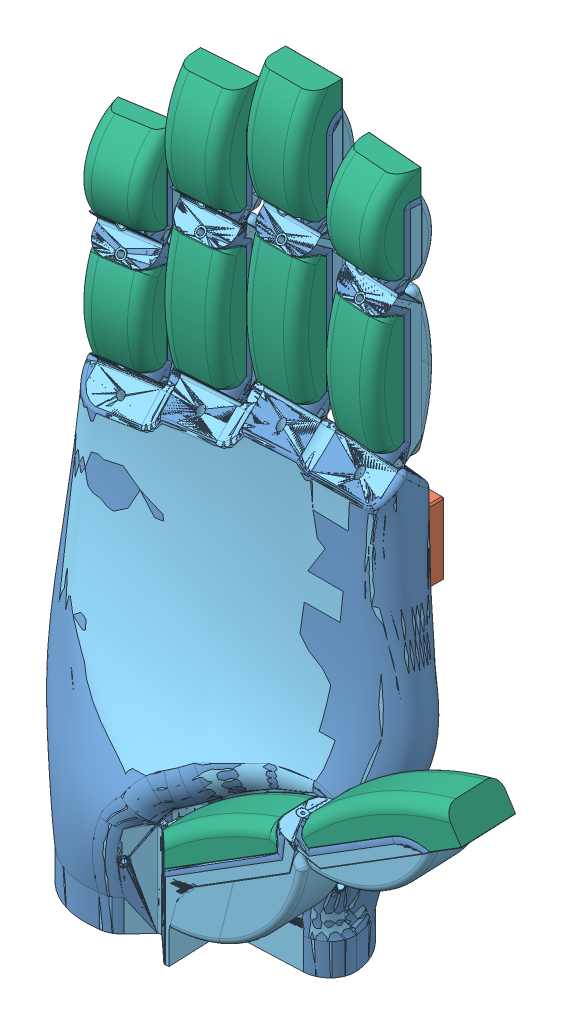
SolidWorks assembly HandAssembly2, configuration Default. Lengths in mm.
Overall size (153.66 227.4 65.45).
29 component instances, 6 part files, 43 mates.
Components (placement in the parent):
- Hand-1: Hand [Default] at origin size (147.58 222.67 61.94)
- ServoAssem-1: ServoAssem [Default] at (17.11 -26.63 -24.3814) x (1 0 0) z (0 -1 0) size (13.8 32.4 32)
  - AGFRC Micro Servo-1: AGFRC Micro Servo [Default] at origin size (12 31.6 32)
  - Pulley-1: Pulley [Default] at (0 28.4 5.5) x (1 0 0) z (0 -1 0) size (13.8 13.8 4)
- ServoAssem-2: ServoAssem [Default] at (-4 -26.63 -24.3814) x (1 0 0) z (0 -1 0) size (13.8 32.4 32)
  - AGFRC Micro Servo-1: AGFRC Micro Servo [Default] at origin size (12 31.6 32)
  - Pulley-1: Pulley [Default] at (0 28.4 5.5) x (1 0 0) z (0 -1 0) size (13.8 13.8 4)
- ServoAssem-3: ServoAssem [Default] at (-20.229 -26.63 -24.3814) x (1 0 0) z (0 -1 0) size (13.8 32.4 32)
  - AGFRC Micro Servo-1: AGFRC Micro Servo [Default] at origin size (12 31.6 32)
  - Pulley-1: Pulley [Default] at (0 28.4 5.5) x (1 0 0) z (0 -1 0) size (13.8 13.8 4)
- ServoAssem-4: ServoAssem [Default] at (-38.46 -26.63 -24.3814) x (1 0 0) z (0 -1 0) size (13.8 32.4 32)
  - AGFRC Micro Servo-1: AGFRC Micro Servo [Default] at origin size (12 31.6 32)
  - Pulley-1: Pulley [Default] at (0 28.4 5.5) x (1 0 0) z (0 -1 0) size (13.8 13.8 4)
- ServoAssem-6: ServoAssem [Default] at (1.5 -77.13 -24.3814) x (0 -1 0) z (-1 0 0) size (13.8 32.4 32)
  - AGFRC Micro Servo-1: AGFRC Micro Servo [Default] at origin size (12 31.6 32)
  - Pulley-1: Pulley [Default] at (0 28.4 5.5) x (1 0 0) z (0 -1 0) size (13.8 13.8 4)
- ServoAssem-7: ServoAssem [Default] at (1.4 -114.356 -2.7814) x (0 0 -1) z (0 1 0) size (13.8 32.4 32)
  - AGFRC Micro Servo-1: AGFRC Micro Servo [Default] at origin size (12 31.6 32)
  - Pulley-1: Pulley [Default] at (0 28.4 5.5) x (1 0 0) z (0 -1 0) size (13.8 13.8 4)
- SensorPCB-1: SensorPCB [Default] at (25.2355 63.12 -1.7931) x (0.996917 0 0.078459) z (0 -1 0) size (12.4 3.2 10.5)
- SensorPCB-2: SensorPCB [Default] at (25.2355 23.12 -1.7931) x (0.996917 0 0.078459) z (0 -1 0) size (12.4 3.2 10.5)
- SensorPCB-6: SensorPCB [Default] at (0 70.75 -1.6) x (1 0 0) z (0 -1 0) size (12.4 3.2 10.5)
- SensorPCB-8: SensorPCB [Default] at (0 25.5 -1.6) x (1 0 0) z (0 -1 0) size (12.4 3.2 10.5)
- SensorPCB-10: SensorPCB [Default] at (-24.3431 60.45 0.1261) x (0.997453 0 -0.071323) z (0 -1 0) size (12.4 3.2 10.5)
- SensorPCB-12: SensorPCB [Default] at (-24.7221 10.21 0.1532) x (-0.997453 0 0.071323) z (0 1 0) size (12.4 3.2 10.5)
- SensorPCB-14: SensorPCB [Default] at (-46.7194 41.62 3.7142) x (0.986771 0 -0.162121) z (0 -1 0) size (12.4 3.2 10.5)
- SensorPCB-16: SensorPCB [Default] at (-46.7194 7.27 3.7142) x (0.986771 0 -0.162121) z (0 -1 0) size (12.4 3.2 10.5)
- RidgedBackPlates-1: RidgedBackPlates [Default] at origin size (147.58 222.67 61.94)
- SquishyFrontPieces-1: SquishyFrontPieces [Default] at origin size (143.98 202.57 46.2)
Mates (geometry in assembly coordinates):
- Width1: width anti-aligned: plane of Hand-1 through (23.61 -50.13 46.9567) normal (-1 0 0); plane of ServoAssem-1/AGFRC Micro Servo-1 through (10.61 -50.13 46.9567) normal (1 0 0); plane of Hand-1 through (23.11 -26.63 -24.3814) normal (1 0 0); plane of ServoAssem-1/AGFRC Micro Servo-1 through (11.11 -26.63 -24.3814) normal (-1 0 0)
- Width2: width aligned: plane of Hand-1 through (23.61 -50.13 46.9567) normal (0 1 0); plane of ServoAssem-1/AGFRC Micro Servo-1 through (10.61 -26.13 46.9567) normal (0 -1 0); plane of Hand-1 through (23.11 -26.63 -24.3814) normal (0 1 0); plane of ServoAssem-1/AGFRC Micro Servo-1 through (23.11 -49.63 -24.3814) normal (0 -1 0)
- Coincident1: coincident anti-aligned: plane of Hand-1 through (0 0 -2.4814) normal (0 0 -1); plane of ServoAssem-1/AGFRC Micro Servo-1 through (23.11 -26.63 -2.4814) normal (0 0 1)
- Width3: width anti-aligned: plane of Hand-1 through (-10.5 -50.13 46.9567) normal (1 0 0); plane of ServoAssem-2/AGFRC Micro Servo-1 through (2.5 -50.13 46.9567) normal (-1 0 0); plane of Hand-1 through (2 -26.63 -24.3814) normal (1 0 0); plane of ServoAssem-2/AGFRC Micro Servo-1 through (-10 -26.63 -24.3814) normal (-1 0 0)
- Width4: width aligned: plane of Hand-1 through (2.5 -50.13 46.9567) normal (0 1 0); plane of ServoAssem-2/AGFRC Micro Servo-1 through (2.5 -26.13 46.9567) normal (0 -1 0); plane of Hand-1 through (2 -26.63 -24.3814) normal (0 1 0); plane of ServoAssem-2/AGFRC Micro Servo-1 through (2 -49.63 -24.3814) normal (0 -1 0)
- Coincident2: coincident anti-aligned: plane of Hand-1 through (0 0 -2.4814) normal (0 0 -1); plane of ServoAssem-2/AGFRC Micro Servo-1 through (2 -26.63 -2.4814) normal (0 0 1)
- Coincident3: coincident anti-aligned: plane of Hand-1 through (0 0 -2.4814) normal (0 0 -1); plane of ServoAssem-3/AGFRC Micro Servo-1 through (-14.229 -26.63 -2.4814) normal (0 0 1)
- Width5: width anti-aligned: plane of Hand-1 through (-26.729 -50.13 46.9567) normal (1 0 0); plane of ServoAssem-3/AGFRC Micro Servo-1 through (-13.729 -50.13 46.9567) normal (-1 0 0); plane of Hand-1 through (-14.229 -26.63 -24.3814) normal (1 0 0); plane of ServoAssem-3/AGFRC Micro Servo-1 through (-26.229 -26.63 -24.3814) normal (-1 0 0)
- Width6: width aligned: plane of Hand-1 through (-13.729 -50.13 46.9567) normal (0 1 0); plane of ServoAssem-3/AGFRC Micro Servo-1 through (-13.729 -26.13 46.9567) normal (0 -1 0); plane of Hand-1 through (-14.229 -26.63 -24.3814) normal (0 1 0); plane of ServoAssem-3/AGFRC Micro Servo-1 through (-14.229 -49.63 -24.3814) normal (0 -1 0)
- Coincident4: coincident anti-aligned: plane of Hand-1 through (0 0 -2.4814) normal (0 0 -1); plane of ServoAssem-4/AGFRC Micro Servo-1 through (-32.46 -26.63 -2.4814) normal (0 0 1)
- Width7: width anti-aligned: plane of Hand-1 through (-44.96 -50.13 46.9567) normal (1 0 0); plane of ServoAssem-4/AGFRC Micro Servo-1 through (-31.96 -26.13 46.9567) normal (-1 0 0); plane of Hand-1 through (-32.46 -26.63 -24.3814) normal (1 0 0); plane of ServoAssem-4/AGFRC Micro Servo-1 through (-44.46 -26.63 -24.3814) normal (-1 0 0)
- Width8: width aligned: plane of Hand-1 through (-31.96 -50.13 46.9567) normal (0 1 0); plane of ServoAssem-4/AGFRC Micro Servo-1 through (-31.96 -26.13 46.9567) normal (0 -1 0); plane of Hand-1 through (-32.46 -26.63 -24.3814) normal (0 1 0); plane of ServoAssem-4/AGFRC Micro Servo-1 through (-32.46 -49.63 -24.3814) normal (0 -1 0)
- Width13: width anti-aligned: plane of Hand-1 through (2 -83.63 46.9567) normal (0 1 0); plane of ServoAssem-6/AGFRC Micro Servo-1 through (-22 -70.63 46.9567) normal (0 -1 0); plane of Hand-1 through (1.5 -83.13 -24.3814) normal (0 -1 0); plane of ServoAssem-6/AGFRC Micro Servo-1 through (1.5 -71.13 -24.3814) normal (0 1 0)
- Width14: width aligned: plane of Hand-1 through (-22 -83.63 46.9567) normal (1 0 0); plane of ServoAssem-6/AGFRC Micro Servo-1 through (2 -83.63 46.9567) normal (-1 0 0); plane of Hand-1 through (1.5 -83.13 -24.3814) normal (1 0 0); plane of ServoAssem-6/AGFRC Micro Servo-1 through (-21.5 -83.13 -24.3814) normal (-1 0 0)
- Coincident6: coincident anti-aligned: plane of Hand-1 through (0 0 -2.4814) normal (0 0 -1); plane of ServoAssem-6/AGFRC Micro Servo-1 through (1.5 -83.13 -2.4814) normal (0 0 1)
- Width16: width aligned: plane of Hand-1 through (1.9 -90.856 46.9567) normal (-1 0 0); plane of ServoAssem-7/AGFRC Micro Servo-1 through (-26.5 -128.856 -0.4814) normal (1 0 0); plane of Hand-1 through (-26 -114.356 -8.7814) normal (-1 0 0); plane of ServoAssem-7/AGFRC Micro Servo-1 through (1.4 -114.356 -8.7814) normal (1 0 0)
- Parallel1: parallel aligned: plane of Hand-1 through (0 0 -2.4814) normal (0 0 -1); plane of ServoAssem-7/AGFRC Micro Servo-1 through (1.4 -114.356 -8.7814) normal (0 0 -1)
- Coincident7: coincident anti-aligned: plane of Hand-1 through (23.11 -26.63 3.2186) normal (0 0 -1); plane of ServoAssem-7/AGFRC Micro Servo-1 through (1.4 -114.356 3.2186) normal (0 0 1)
- Concentric3: concentric aligned: cylinder of Hand-1 through (-14.2544 -116.856 -6.2814) axis (-1 0 0) radius 0.9; cylinder of ServoAssem-7/AGFRC Micro Servo-1 through (1.4 -116.856 -6.2814) axis (-1 0 0) radius 1.25
- Width18: width aligned: plane of Hand-1 through (19.2105 64.8 -6.6819) normal (0.996917 0 0.078459); plane of SensorPCB-1 through (31.5723 54.3 -5.709) normal (-0.996917 0 -0.078459); plane of Hand-1 through (31.1015 64.8 0.2735) normal (0.996917 0 0.078459); plane of SensorPCB-1 through (18.7397 64.8 -0.6994) normal (-0.996917 0 -0.078459)
- Width19: width anti-aligned: plane of Hand-1 through (19.2105 54.3 -6.6819) normal (0 1 0); plane of SensorPCB-1 through (31.5723 64.8 -5.709) normal (0 -1 0); plane of Hand-1 through (18.7397 54.3 -0.6994) normal (0 -1 0); plane of SensorPCB-1 through (18.7397 64.8 -0.6994) normal (0 1 0)
- Coincident8: coincident anti-aligned: plane of Hand-1 through (-24.0026 -0.88 -4.0632) normal (0.078459 0 -0.996917); plane of SensorPCB-1 through (25.11 63.12 -0.198) normal (-0.078459 0 0.996917)
- Width20: width aligned: plane of Hand-1 through (19.2105 24.8 -6.6819) normal (0.996917 0 0.078459); plane of SensorPCB-2 through (31.5723 14.3 -5.709) normal (-0.996917 0 -0.078459); plane of Hand-1 through (31.1015 24.8 0.2735) normal (0.996917 0 0.078459); plane of SensorPCB-2 through (18.7397 24.8 -0.6994) normal (-0.996917 0 -0.078459)
- Width21: width anti-aligned: plane of Hand-1 through (19.2105 14.3 -6.6819) normal (0 1 0); plane of SensorPCB-2 through (31.5723 24.8 -5.709) normal (0 -1 0); plane of Hand-1 through (18.7397 14.3 -0.6994) normal (0 -1 0); plane of SensorPCB-2 through (18.7397 24.8 -0.6994) normal (0 1 0)
- Coincident9: coincident anti-aligned: plane of Hand-1 through (-24.0026 -0.88 -4.0632) normal (0.078459 0 -0.996917); plane of SensorPCB-2 through (25.11 23.12 -0.198) normal (-0.078459 0 0.996917)
- Width24: width anti-aligned: plane of Hand-1 through (6.01 61.93 -6.001) normal (-1 0 0); plane of SensorPCB-6 through (-6.39 72.43 -6.001) normal (1 0 0); plane of Hand-1 through (6.01 72.43 0) normal (1 0 0); plane of SensorPCB-6 through (-6.39 72.43 0) normal (-1 0 0)
- Width26: width anti-aligned: plane of Hand-1 through (-6.39 61.93 -6.001) normal (0 1 0); plane of SensorPCB-6 through (6.01 72.43 -6.001) normal (0 -1 0); plane of Hand-1 through (-6.39 61.93 0) normal (0 -1 0); plane of SensorPCB-6 through (-6.39 72.43 0) normal (0 1 0)
- Coincident11: coincident anti-aligned: plane of Hand-1 through (-51.3632 0 0) normal (0 0 -1); plane of SensorPCB-6 through (0 70.75 0) normal (0 0 1)
- Width27: width aligned: plane of Hand-1 through (-6.39 27.18 -6.001) normal (1 0 0); plane of SensorPCB-8 through (6.01 16.68 -6.001) normal (-1 0 0); plane of Hand-1 through (6.01 27.18 0) normal (1 0 0); plane of SensorPCB-8 through (-6.39 27.18 0) normal (-1 0 0)
- Width28: width anti-aligned: plane of Hand-1 through (-6.39 16.68 -6.001) normal (0 1 0); plane of SensorPCB-8 through (6.01 27.18 -6.001) normal (0 -1 0); plane of Hand-1 through (-6.39 16.68 0) normal (0 -1 0); plane of SensorPCB-8 through (-6.39 27.18 0) normal (0 1 0)
- Coincident12: coincident anti-aligned: plane of Hand-1 through (-51.3632 0 0) normal (0 0 -1); plane of SensorPCB-8 through (0 25.5 0) normal (0 0 1)
- Width29: width aligned: plane of Hand-1 through (-31.0307 62.13 -3.808) normal (0.997453 0 -0.071323); plane of SensorPCB-10 through (-18.6623 51.63 -4.6924) normal (-0.997453 0 0.071323); plane of Hand-1 through (-18.2343 62.13 1.2933) normal (0.997453 0 -0.071323); plane of SensorPCB-10 through (-30.6027 62.13 2.1778) normal (-0.997453 0 0.071323)
- Width30: width aligned: plane of Hand-1 through (-18.6623 62.13 -4.6924) normal (0 -1 0); plane of SensorPCB-10 through (-31.0307 51.63 -3.808) normal (0 1 0); plane of Hand-1 through (-30.6027 51.63 2.1778) normal (0 -1 0); plane of SensorPCB-10 through (-30.6027 62.13 2.1778) normal (0 1 0)
- Coincident13: coincident anti-aligned: plane of Hand-1 through (-74.2051 -7.25 5.2956) normal (-0.071323 0 -0.997453); plane of SensorPCB-10 through (-24.229 60.45 1.722) normal (0.071323 0 0.997453)
- Width31: width aligned: plane of Hand-1 through (-18.6623 8.53 -4.6924) normal (-0.997453 0 0.071323); plane of SensorPCB-12 through (-31.0307 19.03 -3.808) normal (0.997453 0 -0.071323); plane of Hand-1 through (-30.6027 8.53 2.1778) normal (-0.997453 0 0.071323); plane of SensorPCB-12 through (-18.2343 8.53 1.2933) normal (0.997453 0 -0.071323)
- Width32: width aligned: plane of Hand-1 through (-18.6623 19.03 -4.6924) normal (0 -1 0); plane of SensorPCB-12 through (-31.0307 8.53 -3.808) normal (0 1 0); plane of Hand-1 through (-18.2343 19.03 1.2933) normal (0 1 0); plane of SensorPCB-12 through (-18.2343 8.53 1.2933) normal (0 -1 0)
- Coincident14: coincident anti-aligned: plane of Hand-1 through (-74.2051 -7.25 5.2956) normal (-0.071323 0 -0.997453); plane of SensorPCB-12 through (-24.608 10.21 1.7491) normal (0.071323 0 0.997453)
- Width33: width aligned: plane of Hand-1 through (-53.7384 43.3 0.4073) normal (0.986771 0 -0.162121); plane of SensorPCB-14 through (-41.5024 32.8 -1.603) normal (-0.986771 0 0.162121); plane of Hand-1 through (-40.5295 43.3 4.3187) normal (0.986771 0 -0.162121); plane of SensorPCB-14 through (-52.7655 43.3 6.329) normal (-0.986771 0 0.162121)
- Width34: width aligned: plane of Hand-1 through (-41.5024 43.3 -1.603) normal (0 -1 0); plane of SensorPCB-14 through (-53.7384 32.8 0.4073) normal (0 1 0); plane of Hand-1 through (-52.7655 32.8 6.329) normal (0 -1 0); plane of SensorPCB-14 through (-52.7655 43.3 6.329) normal (0 1 0)
- Coincident15: coincident anti-aligned: plane of Hand-1 through (-88.7388 -12.13 12.2391) normal (-0.162121 0 -0.986771); plane of SensorPCB-14 through (-46.46 41.62 5.293) normal (0.162121 0 0.986771)
- Width35: width aligned: plane of Hand-1 through (-53.7384 8.95 0.4073) normal (0.986771 0 -0.162121); plane of SensorPCB-16 through (-41.5024 -1.55 -1.603) normal (-0.986771 0 0.162121); plane of Hand-1 through (-40.5295 8.95 4.3187) normal (0.986771 0 -0.162121); plane of SensorPCB-16 through (-52.7655 8.95 6.329) normal (-0.986771 0 0.162121)
- Width36: width anti-aligned: plane of Hand-1 through (-53.7384 -1.55 0.4073) normal (0 1 0); plane of SensorPCB-16 through (-41.5024 8.95 -1.603) normal (0 -1 0); plane of Hand-1 through (-52.7655 -1.55 6.329) normal (0 -1 0); plane of SensorPCB-16 through (-52.7655 8.95 6.329) normal (0 1 0)
- Coincident16: coincident anti-aligned: plane of Hand-1 through (-88.7388 -12.13 12.2391) normal (-0.162121 0 -0.986771); plane of SensorPCB-16 through (-46.46 7.27 5.293) normal (0.162121 0 0.986771)
